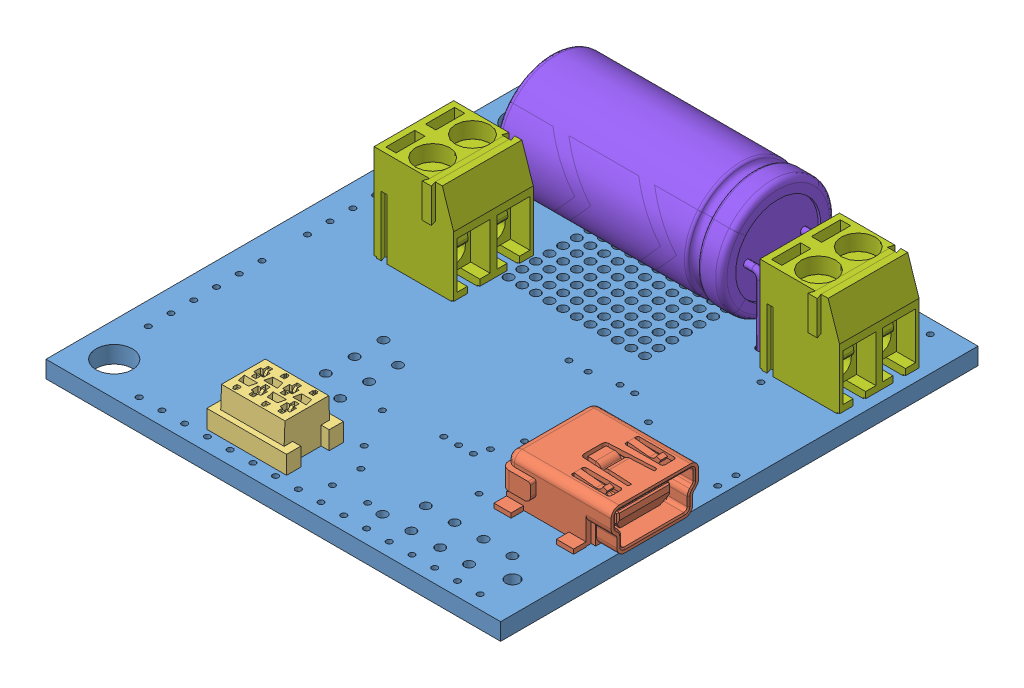
SolidWorks assembly board_light, configuration Default. Lengths in mm.
Overall size (42.77 15.53 42).
9 component instances, 8 part files, 15 mates.
Components (placement in the parent):
- pcb-1: pcb [Default] at (-55.286 17.7924 27.0225) size (40 1.5 42)
- c-1734035-2-b-3d-1: c-1734035-2-b-3d [Default] at (-15.0125 21.2924 13.7305) x (0 0 -1) z (1 0 0) size (9.9 5.09 9.49)
- 11151-1: 11151 [Default] at (-39.3612 18.7924 22.7864) size (7.01 7 5)
- User Library-HSOP_20pin_IC-MC33886PVW-1: User Library-HSOP_20pin_IC-MC33886PVW [Default] at (-35.1619 16.3924 -3.1714) x (1 0 0) z (0 0 -1) size (16 3.2 14.25)
- User Library-SMD CAPACITOR0603-5: User Library-SMD CAPACITOR0603 [0603] at (-33.4292 19.6924 -9.2019) x (0 0 -1) z (1 0 0) size (1.6 0.8 0.8)
- User Library-RESC1608X05N-6: User Library-RESC1608X05N [Default] at (-31.887 19.2924 -9.1984) x (0 0 -1) z (0 1 0) size (1.55 0.85 0.45)
- terminal_blocks_a-tb350-te02-1: terminal_blocks_a-tb350-te02 [Default] at (-48.6576 19.2924 1.2812) x (0 0 -1) z (1 0 0) size (7.99 12.19 7)
- terminal_blocks_a-tb350-te02-2: terminal_blocks_a-tb350-te02 [Default] at (-23.1202 19.2924 -7.1272) x (0 0 -1) z (1 0 0) size (7.99 12.19 7)
- capacitor10x20-1: capacitor10x20 [Default] at (-25.6867 25.1176 -7.7993) x (0 0 1) z (0 -1 0) size (10 33.17 13.5)
Mates (geometry in assembly coordinates):
- Coincident1: coincident anti-aligned: plane of pcb-1 through (-55.286 19.2924 -14.9775) normal (0 1 0); plane of c-1734035-2-b-3d-1 through (-18.7425 19.2924 9.9025) normal (0 -1 0)
- Parallel1: parallel aligned: plane of pcb-1 through (-15.286 19.2924 27.0225) normal (1 0 0); plane of c-1734035-2-b-3d-1 through (-15.0125 19.2644 17.7345) normal (1 0 0)
- Coincident4: coincident anti-aligned: plane of pcb-1 through (-55.286 19.2924 -14.9775) normal (0 1 0); plane of 11151-1 through (-36.5712 19.2924 21.5364) normal (0 -1 0)
- Coincident22: coincident anti-aligned: plane of pcb-1 through (-55.286 17.7924 -14.9775) normal (0 -1 0); plane of User Library-HSOP_20pin_IC-MC33886PVW-1 through (-29.2369 17.7924 3.3536) normal (0 1 0)
- Parallel7: parallel aligned: plane of pcb-1 through (-15.286 19.2924 27.0225) normal (1 0 0); plane of User Library-HSOP_20pin_IC-MC33886PVW-1 through (-27.1619 16.6924 1.2786) normal (1 0 0)
- Coincident52: coincident anti-aligned: plane of pcb-1 through (-55.286 19.2924 -14.9775) normal (0 1 0); plane of User Library-SMD CAPACITOR0603-5 through (-33.0292 19.2924 -10.0019) normal (0 -1 0)
- Parallel17: parallel aligned: plane of pcb-1 through (-55.286 19.2924 -14.9775) normal (0 0 -1); plane of User Library-SMD CAPACITOR0603-5 through (-33.8292 20.0924 -10.0019) normal (0 0 -1)
- Coincident55: coincident anti-aligned: plane of pcb-1 through (-55.286 19.2924 -14.9775) normal (0 1 0); plane of User Library-RESC1608X05N-6 through (-31.462 19.2924 -9.8234) normal (0 -1 0)
- Parallel18: parallel aligned: plane of pcb-1 through (-55.286 19.2924 -14.9775) normal (0 0 -1); plane of User Library-RESC1608X05N-6 through (-31.462 19.5174 -9.9734) normal (0 0 -1)
- Coincident116: coincident anti-aligned: plane of pcb-1 through (-55.286 19.2924 -14.9775) normal (0 1 0); plane of terminal_blocks_a-tb350-te02-1 through (-41.8618 19.2924 -2.2188) normal (0 -1 0)
- Parallel41: parallel aligned: plane of pcb-1 through (-55.286 19.2924 27.0225) normal (-1 0 0); plane of terminal_blocks_a-tb350-te02-1 through (-48.6576 27.6883 -2.2188) normal (-1 0 0)
- Parallel42: parallel aligned: plane of pcb-1 through (-15.286 19.2924 27.0225) normal (1 0 0); plane of terminal_blocks_a-tb350-te02-2 through (-16.1202 24.6922 -10.6272) normal (1 0 0)
- Coincident119: coincident anti-aligned: plane of pcb-1 through (-55.286 19.2924 -14.9775) normal (0 1 0); plane of terminal_blocks_a-tb350-te02-2 through (-16.3245 19.2924 -10.6272) normal (0 -1 0)
- Concentric1: concentric anti-aligned: cylinder of pcb-1 through (-24.6867 17.7914 -5.2993) axis (0 1 0) radius 0.4064; cylinder of capacitor10x20-1 through (-24.6867 24.6176 -5.2993) axis (0 -1 0) radius 0.3
- Parallel45: parallel aligned: plane of pcb-1 through (-15.286 19.2924 27.0225) normal (1 0 0); plane of capacitor10x20-1 through (-25.9367 25.1176 -7.7993) normal (1 0 0)
